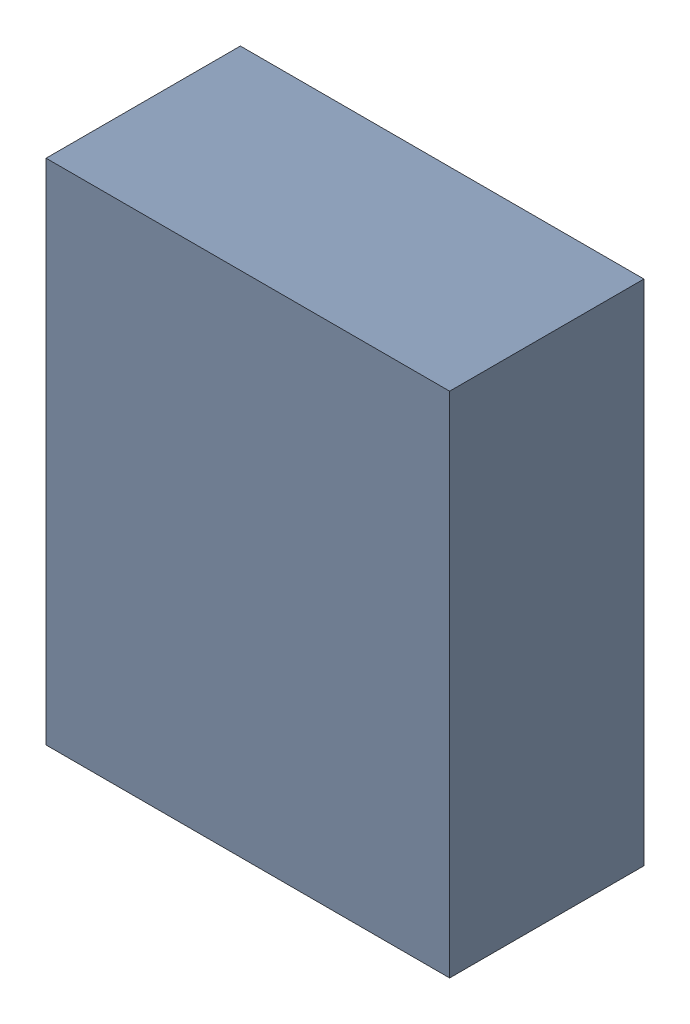
SolidWorks assembly C13, configuration Default. Lengths in mm.
Overall size (2.7 3.4 1.3).
2 component instances, 1 part files, 0 mates.
Components (placement in the parent):
- 468161424-1: 468161424 [Default] at (32.0548 66.2432 -2.4024) size (2.7 3.4 1.3)
  - Extruded_32-1: Extruded_32 [Default] at origin size (2.7 3.4 1.3)
